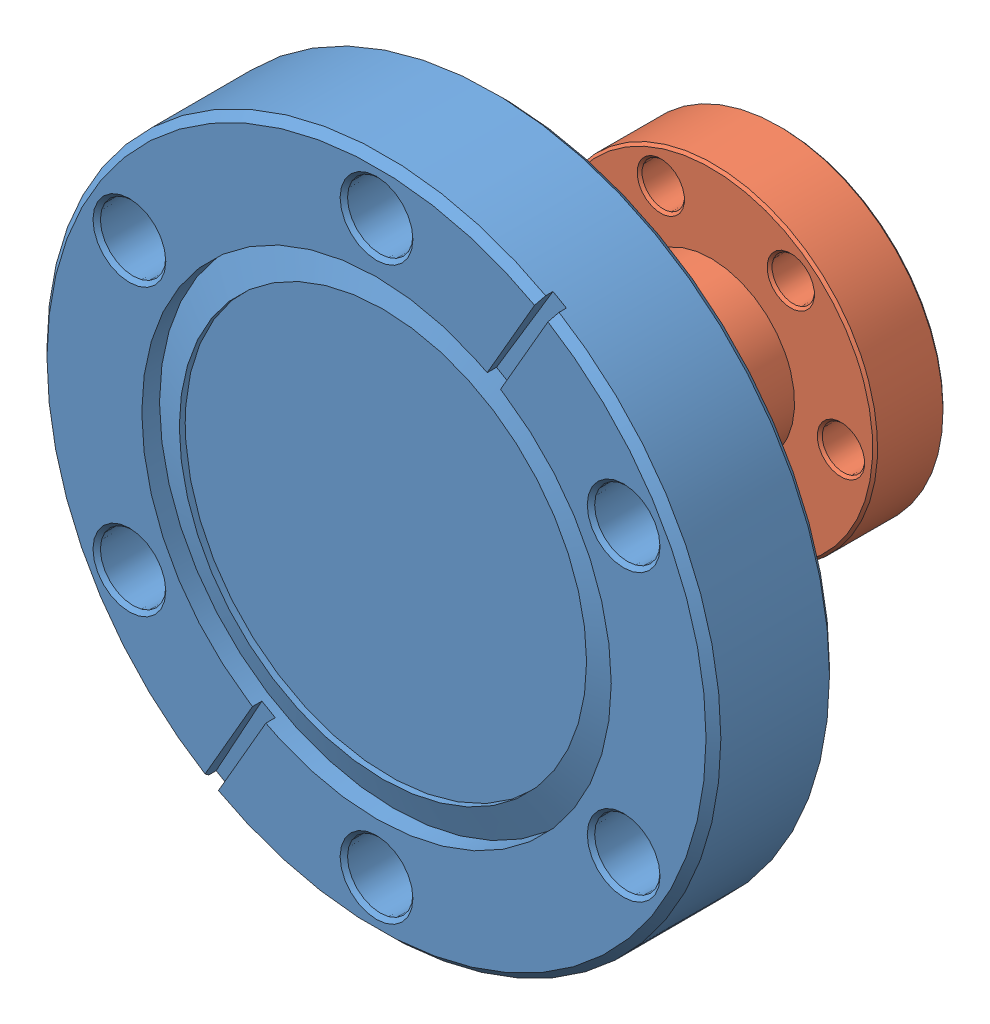
SolidWorks assembly Er Source P1, configuration Default. Lengths in mm.
Overall size (69.34 69.34 41.66).
2 component instances, 2 part files, 2 mates.
Components (placement in the parent):
- Er Source P1-2_110008-1: Er Source P1-2_110008 [Default] at (13.1702 33.8948 67.8415) size (69.34 69.34 12.7)
- Er Source P1-1_110002-1: Er Source P1-1_110002 [Default] at (13.1702 33.8948 26.1855) x (-0.923728 -0.383049 0) z (0 0 -1) size (33.78 33.78 28.96)
Mates (geometry in assembly coordinates):
- Coincident2: coincident anti-aligned: plane of Er Source P1-2_110008-1 through (13.1702 33.8948 55.1415) normal (0 0 -1); plane of Er Source P1-1_110002-1 through (13.1702 33.8948 55.1415) normal (0 0 1)
- Concentric2: concentric anti-aligned: circle of Er Source P1-2_110008-1; circle of Er Source P1-1_110002-1
